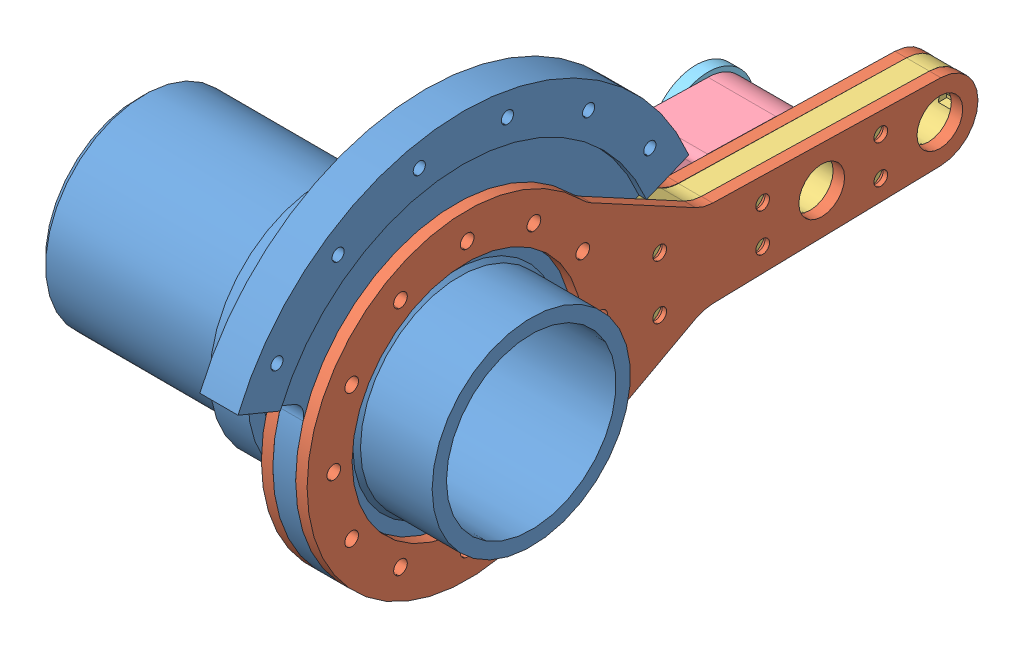
SolidWorks assembly hip-front-new-left-2012-09-04, configuration Default. Lengths in mm.
Overall size (51.7 93.39 166.65).
7 component instances, 6 part files, 17 mates.
Components (placement in the parent):
- abs-hip-front-2012-11-20-1: abs-hip-front-2012-11-20 [Default] at (-57.0839 1.2367 -1.8747) size (51.7 53 129.22)
- carbon-plat-hip-front-1: carbon-plat-hip-front [Default] at (-60.0839 1.2367 -1.8747) x (0 0 -1) z (1 0 0) size (88 42 1.5)
- carbon-plat-hip-front-2: carbon-plat-hip-front [Default] at (-55.5839 1.2367 -1.8747) x (0 0 -1) z (1 0 0) size (88 42 1.5)
- Hip_gear-1: Hip_gear [Default] at (-58.0839 1.2367 -1.8747) x (1 0 0) z (0 -0.382683 -0.92388) size (9 71.48 71.48)
- Pom-plat-hip-front-04-03-13-1: Pom-plat-hip-front-04-03-13 [Default] at (-58.5839 1.2367 -1.8747) x (0 0 -1) z (1 0 0) size (49.97 22.69 3)
- distancepiece_legsprings_011112_Mill_Pom-1: distancepiece_legsprings_011112_Mill_Pom [Default] at (-64.5339 1.2367 -48.3747) x (0 -1 0) z (-1 0 0) size (11.24 15.4 8.9)
- Washer-d6p5-12-1: Washer-d6p5-12 [Défaut] at (-69.7839 1.2367 -48.3747) x (0 0 1) z (-1 0 0) size (12 12 1.6)
Mates (geometry in assembly coordinates):
- Coincident1: coincident anti-aligned: plane of abs-hip-front-2012-11-20-1 through (-58.5839 6.2116 10.1357) normal (-1 0 0); plane of carbon-plat-hip-front-1 through (-58.5839 1.2367 -63.8747) normal (1 0 0)
- Concentric1: concentric aligned: cylinder of abs-hip-front-2012-11-20-1 through (-57.0839 1.2367 -1.8747) axis (-1 0 0) radius 13; cylinder of carbon-plat-hip-front-1 through (-58.5839 1.2367 -1.8747) axis (-1 0 0) radius 15.1
- Concentric2: concentric aligned: cylinder of abs-hip-front-2012-11-20-1 through (-57.0839 1.2367 -1.8747) axis (-1 0 0) radius 13; cylinder of carbon-plat-hip-front-2 through (-54.0839 1.2367 -1.8747) axis (-1 0 0) radius 15.1
- Coincident2: coincident anti-aligned: plane of abs-hip-front-2012-11-20-1 through (-55.5839 6.2116 10.1357) normal (1 0 0); plane of carbon-plat-hip-front-2 through (-55.5839 1.2367 -63.8747) normal (-1 0 0)
- Concentric3: concentric aligned: cylinder of carbon-plat-hip-front-1 through (-58.5839 1.2367 -63.8747) axis (-1 0 0) radius 3; cylinder of carbon-plat-hip-front-2 through (-54.0839 1.2367 -63.8747) axis (-1 0 0) radius 3
- Concentric4: concentric anti-aligned: cylinder of abs-hip-front-2012-11-20-1 through (-57.0839 1.2367 -1.8747) axis (-1 0 0) radius 32; cylinder of Hip_gear-1 through (-59.5839 1.2367 -1.8747) axis (1 0 0) radius 32
- Parallel1: parallel aligned: plane of carbon-plat-hip-front-1; plane of assembly through (0 0 0) normal (0 1 0)
- Coincident7: coincident anti-aligned: plane of abs-hip-front-2012-11-20-1 through (-59.5839 13.4826 27.6894) normal (-1 0 0); plane of Hip_gear-1 through (-59.5839 25.2576 -11.8245) normal (1 0 0)
- Coincident8: coincident aligned: plane of abs-hip-front-2012-11-20-1 through (-58.5839 13.4826 -31.4389) normal (0 -0.92388 -0.382683); plane of Hip_gear-1 through (-62.5839 1.2367 -1.8747) normal (0 -0.92388 -0.382683)
- Coïncidente1: coincident anti-aligned: plane of carbon-plat-hip-front-1 through (-58.5839 1.2367 -63.8747) normal (1 0 0); plane of Pom-plat-hip-front-04-03-13-1 through (-58.5839 1.2367 -63.8747) normal (-1 0 0)
- Coaxiale1: concentric aligned: cylinder of carbon-plat-hip-front-2 through (-54.0839 1.2367 -63.8747) axis (-1 0 0) radius 3; cylinder of Pom-plat-hip-front-04-03-13-1 through (-55.5839 1.2367 -63.8747) axis (-1 0 0) radius 3
- Coaxiale2: concentric aligned: cylinder of carbon-plat-hip-front-2 through (-54.0839 1.2367 -48.3747) axis (-1 0 0) radius 3; cylinder of Pom-plat-hip-front-04-03-13-1 through (-55.5839 1.2367 -48.3747) axis (-1 0 0) radius 3
- Coaxiale3: concentric aligned: cylinder of Pom-plat-hip-front-04-03-13-1 through (-55.5839 1.2367 -48.3747) axis (-1 0 0) radius 3; cylinder of distancepiece_legsprings_011112_Mill_Pom-1 through (-60.0839 1.2367 -48.3747) axis (-1 0 0) radius 3.05
- Coïncidente3: coincident anti-aligned: plane of carbon-plat-hip-front-1 through (-60.0839 1.2367 -63.8747) normal (-1 0 0); plane of distancepiece_legsprings_011112_Mill_Pom-1 through (-60.0839 1.2367 -48.3747) normal (1 0 0)
- Coaxiale6: concentric aligned: cylinder of carbon-plat-hip-front-2 through (-54.0839 3.7367 -40.6247) axis (1 0 0) radius 0.9; cylinder of distancepiece_legsprings_011112_Mill_Pom-1 through (-60.0839 3.7367 -40.6247) axis (1 0 0) radius 0.625
- Coïncidente5: coincident anti-aligned: plane of distancepiece_legsprings_011112_Mill_Pom-1 through (-68.9839 1.2367 -48.3747) normal (-1 0 0); plane of Washer-d6p5-12-1 through (-68.9839 1.2367 -48.3747) normal (1 0 0)
- Coaxiale8: concentric anti-aligned: cylinder of distancepiece_legsprings_011112_Mill_Pom-1 through (-60.0839 1.2367 -48.3747) axis (-1 0 0) radius 3.05; cylinder of Washer-d6p5-12-1 through (-70.5839 1.2367 -48.3747) axis (1 0 0) radius 3.25
